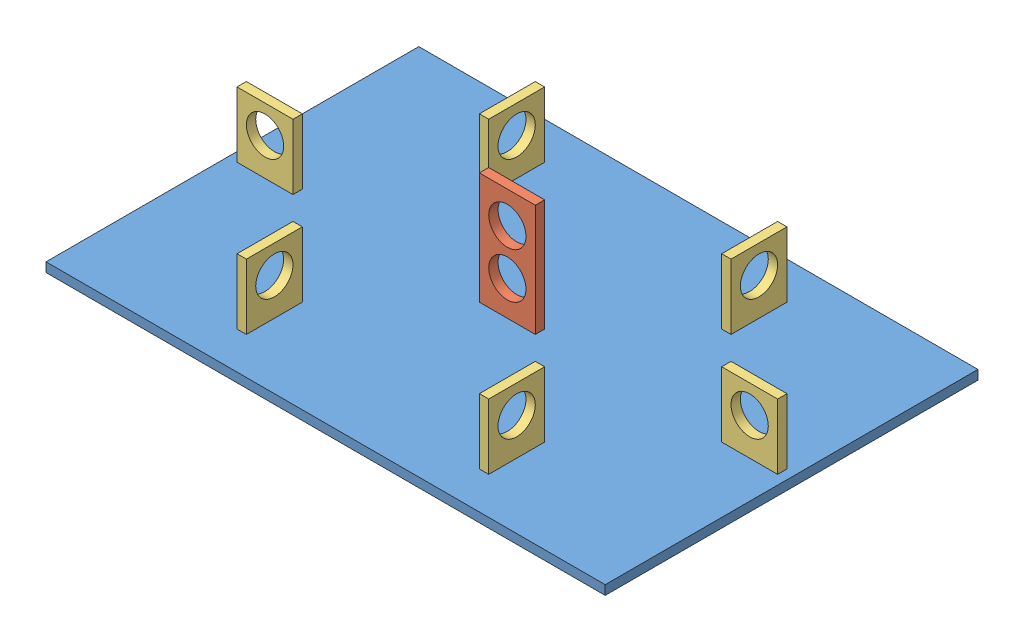
SolidWorks assembly assembly, configuration Default. Lengths in mm.
Overall size (300 65.06 200).
8 component instances, 3 part files, 14 mates.
Components (placement in the parent):
- base-1: base [Default] at (52.9424 170.2732 250.4126) size (300 5 200)
- support central-8: support central [Default] at (52.9479 210.8593 247.9126) size (30 65.06 5)
- support-8: support [Default] at (-77.0576 190.2732 247.9126) size (30 40 5)
- support-9: support [Default] at (-14.5576 190.2732 185.4126) x (0 0 -1) z (1 0 0) size (30 40 5)
- support-10: support [Default] at (-9.5576 190.2732 315.4126) x (0 0 1) z (-1 0 0) size (30 40 5)
- support-11: support [Default] at (115.4424 190.2732 315.4126) x (0 0 -1) z (1 0 0) size (30 40 5)
- support-12: support [Default] at (182.9424 190.2732 247.9126) size (30 40 5)
- support-13: support [Default] at (120.4424 190.2732 185.4126) x (0 0 1) z (-1 0 0) size (30 40 5)
Mates (geometry in assembly coordinates):
- Coincident15: coincident: line of base-1 through (37.9424 170.2732 252.9126) axis (1 0 0); line of support central-8 through (53.2365 170.2732 252.9126) axis (1 0 0)
- Coincident17: coincident aligned: line of base-1 through (-14.5576 170.2732 300.4126) axis (0 0 1); line of support-10 through (-14.5576 170.2732 300.4126) axis (0 0 1)
- Coincident18: coincident anti-aligned: line of base-1 through (-9.5576 170.2732 300.4126) axis (-1 0 0); line of support-10 through (-14.5576 170.2732 300.4126) axis (1 0 0)
- Coincident20: coincident aligned: line of base-1 through (-92.0576 170.2732 252.9126) axis (1 0 0); line of support-8 through (-92.0576 170.2732 252.9126) axis (1 0 0)
- Coincident21: coincident aligned: line of base-1 through (-62.0576 170.2732 252.9126) axis (0 0 -1); line of support-8 through (-62.0576 170.2732 252.9126) axis (0 0 -1)
- Coincident22: coincident aligned: line of base-1 through (-9.5576 170.2732 200.4126) axis (0 0 -1); line of support-9 through (-9.5576 170.2732 200.4126) axis (0 0 -1)
- Coincident23: coincident anti-aligned: line of base-1 through (-14.5576 170.2732 200.4126) axis (1 0 0); line of support-9 through (-9.5576 170.2732 200.4126) axis (-1 0 0)
- Coincident24: coincident aligned: line of base-1 through (120.4424 170.2732 330.4126) axis (0 0 -1); line of support-11 through (120.4424 170.2732 330.4126) axis (0 0 -1)
- Coincident25: coincident anti-aligned: line of base-1 through (115.4424 170.2732 330.4126) axis (1 0 0); line of support-11 through (120.4424 170.2732 330.4126) axis (-1 0 0)
- Coincident26: coincident aligned: line of base-1 through (167.9424 170.2732 252.9126) axis (1 0 0); line of support-12 through (167.9424 170.2732 252.9126) axis (1 0 0)
- Coincident27: coincident anti-aligned: line of base-1 through (167.9424 170.2732 247.9126) axis (0 0 1); line of support-12 through (167.9424 170.2732 252.9126) axis (0 0 -1)
- Coincident28: coincident aligned: line of base-1 through (115.4424 170.2732 170.4126) axis (0 0 1); line of support-13 through (115.4424 170.2732 170.4126) axis (0 0 1)
- Coincident29: coincident anti-aligned: line of base-1 through (120.4424 170.2732 170.4126) axis (-1 0 0); line of support-13 through (115.4424 170.2732 170.4126) axis (1 0 0)
- Coincident30: coincident anti-aligned: line of base-1 through (37.9424 170.2732 247.9126) axis (0 0 1); line of support central-8 through (37.9424 170.2732 252.9126) axis (0 0 -1)
